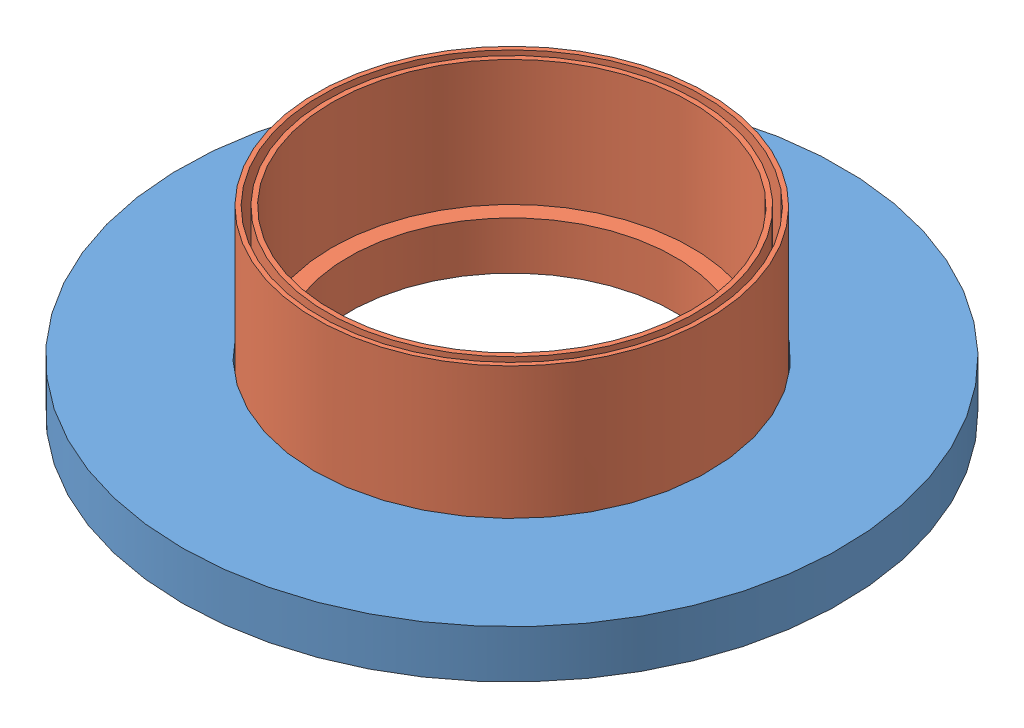
SolidWorks assembly Assemblage1, configuration Défaut. Lengths in mm.
Overall size (525 142.49 525).
3 component instances, 3 part files, 3 mates.
Components (placement in the parent):
- base-3: base [Défaut] at (-66.245 484.3508 1.8199) size (525 82.41 525)
- interne-3: interne [Défaut] at (-66.245 484.0997 1.8199) x (-0.9522 0 -0.305474) z (0.305474 0 -0.9522) size (311.82 138.1 311.82)
- tuyau-2: tuyau [Défaut] at (-64.1718 526.2909 3.5588) size (304.8 120 304.8) (hidden)
Mates (geometry in assembly coordinates):
- Coïncidente5: coincident anti-aligned: plane of interne-3 through (-190.0311 526.2909 -37.8917) normal (0 1 0); plane of tuyau-2 through (-64.1718 526.2909 3.5588) normal (0 -1 0)
- Coaxiale2: concentric anti-aligned: cylinder of base-3 through (-66.245 508.507 1.8199) axis (0 1 0) radius 142.748; cylinder of interne-3 through (-66.245 626.2909 1.8199) axis (0 -1 0) radius 143.1408
- Distance1: distance = 4.3942 mm anti-aligned: plane of interne-3 through (-214.7007 500.8909 -45.8059) normal (0 -1 0); plane of base-3 through (90.727 496.4967 1.8199) normal (0 1 0)
